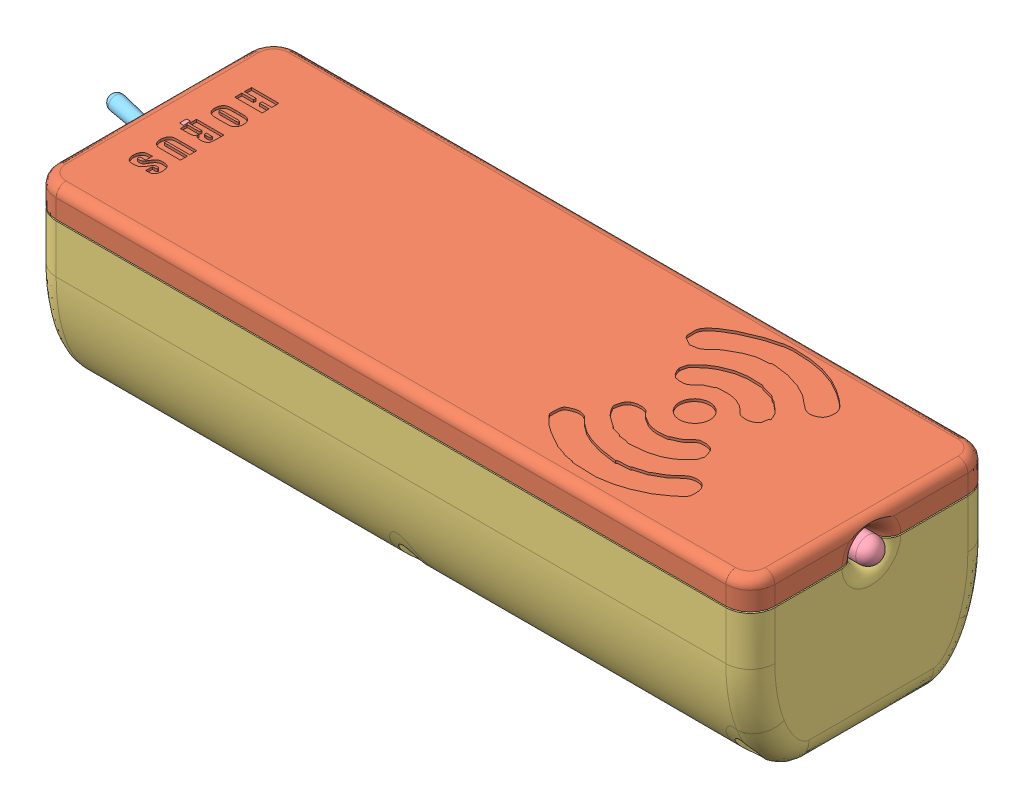
SolidWorks assembly montagem completa, configuration Default. Lengths in mm.
Overall size (159.43 43.59 54.12).
30 component instances, 22 part files, 13 mates.
Components (placement in the parent):
- placa-1: placa [Default] at (97.7154 35.3564 57.9043) x (1 0 0) z (0 -1 0) size (70.1 39.06 34.21)
- bateria-1: bateria [Default] at origin size (79.03 35.23 37.5)
  - bateria-1: bateria [Valor predeterminado] at (23.6654 23.8156 58.3925) size (66 19 37.5)
  - MT3608-Module.stp-1: MT3608-Module.stp [Default] at (41.8628 45.0348 63.9384) x (-1 0 0) z (0 1 0) size (37.01 17.71 6.5)
  - MTS-1xx-A2-blue-OFF.step-1: MTS-1xx-A2-blue-OFF.step [Default] at (7.7654 47.7656 58.3925) x (0 -1 0) z (-1 0 0) size (12 13.4 35.63)
    - eBom-prt0.step-1: eBom-prt0.step [Default] at (0 0 10.3) x (1 0 0) z (0 1 0) size (12 9.99 12.8)
    - Handle.step-1: Handle.step [Default] at (0 0 19.1) x (-1 0 0) z (0 -1 0) size (3.8 17.38 5.93)
    - eBom-prt2.step-1: eBom-prt2.step [Default] at (0 0 4.4) x (-1 0 0) z (0 -1 0) size (3.55 1.36 10.22)
    - L.step-1: L.step [Default] at (0 -0.1062 17.6994) x (1 0 0) z (0 0.978148 0.207912) size (3.55 20.58 3.55)
    - eBom-prt4.step-1: eBom-prt4.step [Default] at (0 0 4.4) size (3.7 10.2 9.9)
    - Housing.step-1: Housing.step [Default] at (0 0 10.3) x (1 0 0) z (0 1 0) size (7.9 10.3 13.2)
  - Lipo Charger - With Load Protection.stp-1: Lipo Charger - With Load Protection.stp [Default] at (3.7972 22.8156 58.3925) x (1 0 0) z (0 -1 0) size (26.91 17.09 4.28)
    - bOARD.stp-1: bOARD.stp [Default] at origin size (26.26 17.09 1.68)
    - 0603 Capacitor.stp-1: 0603 Capacitor.stp [Default] at (1.3663 2.3089 1.5723) x (0 -1 0) z (0 0 1) size (1.6 0.84 0.84)
    - 0603 Resistor.stp-1: 0603 Resistor.stp [Default] at (-2.0999 -6.1665 1.5723) size (1.6 0.85 0.56)
    - 0603 Resistor.stp-2: 0603 Resistor.stp [Default] at (-6.7314 4.6411 1.5723) size (1.6 0.85 0.56)
    - 0805 Capacitor.stp-1: 0805 Capacitor.stp [Default] at (3.543 2.3802 1.5723) x (0 -1 0) z (0 0 1) size (2.01 1.27 0.84)
    - 0603 Capacitor.stp-2: 0603 Capacitor.stp [Default] at (-6.6654 -6.2522 1.5723) size (1.6 0.84 0.84)
    - SOIC-8-150.stp-1: SOIC-8-150.stp [Default] at (-3.5116 0.0462 2.4718) x (-1 0 0) z (0 1 0) size (5 1.75 6.2)
    - LED - 0805 - Blue.stp-1: LED - 0805 - Blue.stp [Default] at (-6.7354 7.0496 1.5448) size (2 1.25 0.83)
    - LED - 0805 - Red.stp-1: LED - 0805 - Red.stp [Default] at (-0.6772 7.1069 1.5448) x (-1 0 0) z (0 0 1) size (2 1.25 0.83)
    - 0603 Resistor.stp-3: 0603 Resistor.stp [Default] at (-2.2661 4.8273 1.5723) size (1.6 0.85 0.56)
    - USB - Micro.stp-1: USB - Micro.stp [Default] at (-7.8617 -2.8878 1.1998) x (0 -1 0) z (-1 0 0) size (7.92 3.01 5.67)
    - tsop8.stp-1: tsop8.stp [Default] at (7.7511 -2.5035 1.4748) x (0 1 0) z (0 0 1) size (6.4 3.1 1.2)
    - sot-23-6-2.stp-1: sot-23-6-2.stp [Default] at (7.8055 3.8715 1.5748) x (0 1 0) z (0 0 1) size (2.43 2.79 1.09)
    - 0603 Resistor.stp-4: 0603 Resistor.stp [Default] at (4.561 -4.8365 1.5723) x (0 1 0) z (0 0 1) size (1.6 0.85 0.56)
    - 0603 Resistor.stp-5: 0603 Resistor.stp [Default] at (3.7053 6.1769 1.5723) x (0 -1 0) z (0 0 1) size (1.6 0.85 0.56)
- tampa-1: tampa [Default] at (61.9654 53.7156 58.2425) x (1 0 0) z (0 0 -1) size (146.62 12.41 49.36)
- caixa-1: caixa [Default] at (61.9654 15.7408 58.2425) size (146.77 36.46 54.12)
- LED 5mm-1: LED 5mm [Valor predeterminado] at (128.2654 47.7656 58.2425) x (0 -0.924225 -0.381849) z (1 0 0) size (5.5 6 35.8)
Mates (geometry in assembly coordinates):
- Coincident1: coordinate: point of bateria-1
- Coincident2: coincident aligned: plane of bateria-1 through (0 0 0) normal (1 0 0)
- Symmetric1: symmetric aligned: plane of placa-1 through (66.1042 46.3564 77.9225) normal (0 0 1); plane of bateria-1/bateria-1 through (125.6842 46.3564 38.8625) normal (0 0 -1); plane of placa-1 through (23.6654 23.8156 58.3925) normal (0 0 1)
- Distance2: distance = 0.5 mm anti-aligned: plane of tampa-1 through (61.9654 52.2156 58.2425) normal (0 -1 0); plane of placa-1 through (74.1042 51.7156 43.8625) normal (0 1 0)
- Coincident3: coincident aligned: plane of placa-1 through (74.1042 51.7156 43.8625) normal (0 1 0); plane of bateria-1/MTS-1xx-A2-blue-OFF.step-1/Housing.step-1 through (-5.7945 51.7156 58.3925) normal (0 1 0)
- Distance3: distance = 1.5 mm anti-aligned: plane of caixa-1 through (61.9654 17.2408 58.2425) normal (0 1 0); plane of bateria-1/Lipo Charger - With Load Protection.stp-1/USB - Micro.stp-1 through (-9.9949 18.7408 61.9171) normal (0 -1 0)
- Concentric1: concentric aligned: circle of tampa-1; circle of LED 5mm-1
- Coincident4: coincident anti-aligned: plane of tampa-1 through (129.2654 53.7156 58.2425) normal (-1 0 0); plane of LED 5mm-1 through (129.2654 47.7656 58.2425) normal (1 0 0)
- Distance4: distance = 5 mm aligned: plane of placa-1 through (66.1042 46.3564 77.9225) normal (0 0 1); plane of tampa-1 through (61.9654 47.8906 82.9225) normal (0 0 1)
- Distance5: distance = 5 mm aligned: plane of caixa-1 through (135.2654 47.6358 82.9225) normal (0 0 1); plane of placa-1 through (66.1042 46.3564 77.9225) normal (0 0 1)
- Distance6: distance = 0.5 mm anti-aligned: plane of caixa-1 through (-9.8346 47.6358 35.0625) normal (1 0 0); plane of bateria-1/bateria-1 through (-9.3346 42.8156 39.6425) normal (-1 0 0)
- Distance7: distance = 68 mm anti-aligned: plane of tampa-1 through (-11.3346 47.8906 58.2425) normal (-1 0 0); plane of bateria-1/bateria-1 through (56.6654 42.8156 39.6425) normal (1 0 0)
- Distance8: distance = 6 mm anti-aligned: plane of bateria-1/bateria-1 through (56.6654 42.8156 39.6425) normal (1 0 0); plane of placa-1 through (62.6654 35.3564 42.8543) normal (-1 0 0)
